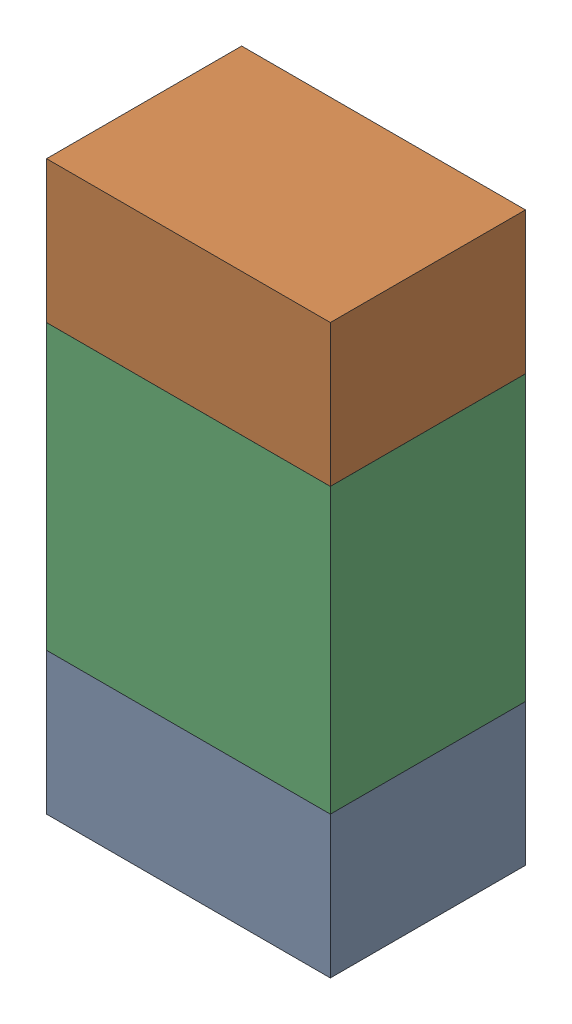
SolidWorks assembly R62, configuration ﾃﾞﾌｫﾙﾄ. Lengths in mm.
Overall size (0.8 1.6 0.55).
6 component instances, 2 part files, 0 mates.
Components (placement in the parent):
- 689261784-1: 689261784 [ﾃﾞﾌｫﾙﾄ] at (42.5999 32.4001 0) size (0.8 0.4 0.55)
  - Extruded_34-1: Extruded_34 [ﾃﾞﾌｫﾙﾄ] at origin size (0.8 0.4 0.55)
- 689261784-2: 689261784 [ﾃﾞﾌｫﾙﾄ] at (42.5999 33.6001 0) size (0.8 0.4 0.55)
  - Extruded_34-1: Extruded_34 [ﾃﾞﾌｫﾙﾄ] at origin size (0.8 0.4 0.55)
- 689261648-1: 689261648 [ﾃﾞﾌｫﾙﾄ] at (42.5999 33 0) size (0.8 0.8 0.55)
  - Extruded_33-1: Extruded_33 [ﾃﾞﾌｫﾙﾄ] at origin size (0.8 0.8 0.55)
